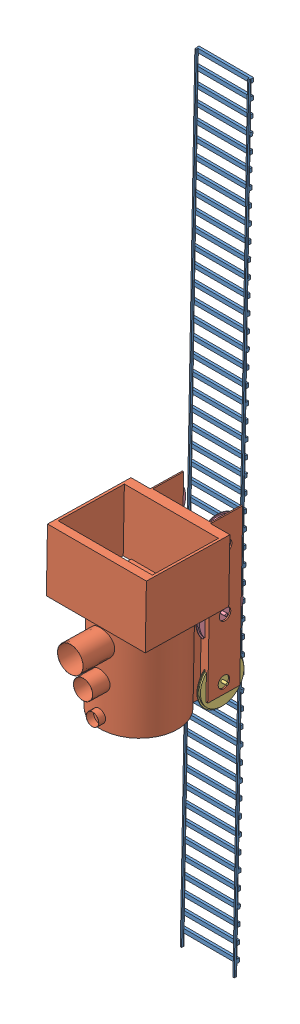
SolidWorks assembly steam train, configuration Default. Lengths in mm.
Overall size (3911.6 30477.98 6307.9).
5 component instances, 4 part files, 13 mates.
Components (placement in the parent):
- track-1: track [Default] at (2772.9709 23289.0272 889.7032) x (1 0 0) z (0 -0.999822 0.018842) size (2159 179.95 30480)
- body-2: body [Default] at (5078.9652 2983.2995 1609.3568) x (1 0 0) z (0 -0.999822 0.018842) size (3911.6 5515.84 6327.9)
- wheel5-1: wheel5 [Default] at (5744.8806 3413.2472 2236.3671) x (1 0 0) z (0 0.141818 0.989893) size (2723.32 1828.8 1828.8)
- wheel6-2: wheel6 [Default] at (5663.1652 5716.8381 2192.9551) size (2723.32 1828.8 1828.8)
- wheel6-3: wheel6 [Default] at (5536.1652 8020.4291 2149.5431) size (2723.32 1828.8 1828.8)
Mates (geometry in assembly coordinates):
- Concentric2: concentric: cylinder of body-2 through (7194.2772 3413.2472 2236.3671) axis (-1 0 0) radius 228.6; cylinder of wheel5-1 through (2691.3652 3413.2472 2236.3671) axis (-1 0 0) radius 50.8
- Coincident7: coincident: plane of track-1 through (2742.1652 -7183.472 1574.9015) normal (1 0 0); plane of wheel5-1 through (2742.1652 4318.4051 2106.6888) normal (-1 0 0)
- Coincident8: coincident: circle of body-2; plane of wheel5-1 through (4926.5652 4318.4051 2106.6888) normal (-1 0 0)
- Tangent3: tangent anti-aligned: plane of track-1 through (4774.1652 -7183.472 1574.9015) normal (0 0.018842 0.999822); cylinder of wheel5-1 through (2691.3652 3413.2472 2236.3671) axis (-1 0 0) radius 861.0115
- Distance2: distance = 101.6 mm: plane of body-2 through (5028.1652 6663.2224 2759.4239) normal (-1 0 0); plane of wheel5-1 through (4926.5652 4318.4051 2106.6888) normal (-1 0 0)
- Concentric3: concentric: cylinder of body-2 through (7194.2772 5716.8381 2192.9551) axis (-1 0 0) radius 228.6; cylinder of wheel6-2 through (2609.6497 5716.8381 2192.9551) axis (-1 0 0) radius 50.8
- Coincident10: coincident: plane of track-1 through (4774.1652 -7184.8677 1500.8434) normal (-1 0 0); plane of wheel6-2 through (4870.2497 6577.8497 2192.9551) normal (1 0 0)
- Tangent4: tangent anti-aligned: plane of track-1 through (4774.1652 -7183.472 1574.9015) normal (0 0.018842 0.999822); cylinder of wheel6-2 through (2609.6497 5716.8381 2192.9551) axis (-1 0 0) radius 861.0115
- Distance3: distance = 101.6 mm: plane of wheel6-2 through (4926.5652 5767.6381 2192.9551) normal (1 0 0); plane of body-2 through (5028.1652 6663.2224 2759.4239) normal (-1 0 0)
- Distance4: distance = 177.8 mm: plane of wheel6-2 through (4926.5652 5767.6381 2192.9551) normal (1 0 0); plane of body-2 through (5028.1652 6663.2224 2759.4239) normal (-1 0 0)
- Concentric4: concentric aligned: cylinder of body-2 through (7194.2772 8020.4291 2149.5431) axis (-1 0 0) radius 228.6; cylinder of wheel6-3 through (2482.6497 8020.4291 2149.5431) axis (-1 0 0) radius 50.8
- Coincident13: coincident: plane of track-1 through (4774.1652 -7184.8677 1500.8434) normal (-1 0 0); plane of wheel6-3 through (4743.2497 8881.4407 2149.5431) normal (1 0 0)
- Distance5: distance = 228.6 mm: plane of wheel6-3 through (4799.5652 8071.2291 2149.5431) normal (1 0 0); plane of body-2 through (5028.1652 6663.2224 2759.4239) normal (-1 0 0)
